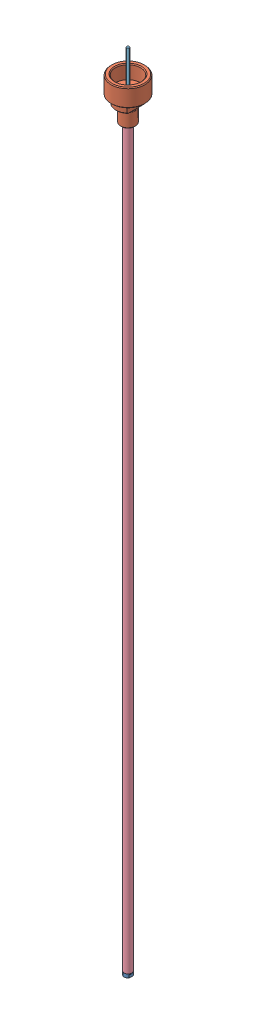
SolidWorks assembly Ensamblaje con tubo pipeta, configuration Predeterminado. Lengths in mm.
Overall size (41.58 1129.12 41.58).
5 component instances, 5 part files, 7 mates.
Components (placement in the parent):
- Boquilla de la Pipeta-1: Boquilla de la Pipeta [Predeterminado] at (-120.7009 -415.5245 82.1761) size (9.52 11 9.52)
- Buje Copa Superior-1: Buje Copa Superior [Predeterminado] at (-120.7009 493.4755 82.1761) size (41.58 52 41.58)
- Buje interior de Boquilla-1: Buje interior de Boquilla [Predeterminado] at (-120.7009 -417.399 82.1761) x (0.243661 0 -0.969861) z (0.969861 0 0.243661) size (6 4 6)
- Tubo Pipeta-1: Tubo Pipeta [Predeterminado] at (-120.7009 495.3348 82.1761) x (1 0 0.000226) z (-0.000226 0 1) size (9.52 940 9.52)
- Varilla de la pipeta-1: Varilla de la pipeta [Predeterminado] at (-120.7009 574.5117 82.1761) size (3.17 1129.12 3.17)
Mates (geometry in assembly coordinates):
- Concéntrica1: concentric aligned: cylinder of Buje Copa Superior-1 through (-120.7009 543.8505 82.1761) axis (0 1 0) radius 4.7625; cylinder of Tubo Pipeta-1 through (-120.7009 532.5941 82.1761) axis (0 1 0) radius 4.26
- Coincidente1: coincident anti-aligned: plane of Buje Copa Superior-1 through (-115.9384 523.4755 82.1761) normal (0 -1 0); plane of Tubo Pipeta-1 through (-116.4409 523.4755 82.1771) normal (0 1 0)
- Coincidente5: coincident: circle of Buje interior de Boquilla-1; cone of Varilla de la pipeta-1 through (-120.7009 -416.4449 82.1761) axis (0 -1 0)
- Coincidente6: coincident anti-aligned: plane of Boquilla de la Pipeta-1 through (-117.7009 -414.5245 82.1761) normal (0 1 0); plane of Buje interior de Boquilla-1 through (-120.3841 -414.5245 80.9153) normal (0 -1 0)
- Concéntrica4: concentric aligned: cylinder of Boquilla de la Pipeta-1 through (-120.7009 -389.2879 82.1761) axis (0 1 0) radius 3; cylinder of Varilla de la pipeta-1 through (-120.7009 585.7954 82.1761) axis (0 1 0) radius 1.5875
- Coincidente7: coincident anti-aligned: plane of Boquilla de la Pipeta-1 through (-115.9409 -410.5245 82.1761) normal (0 1 0); plane of Tubo Pipeta-1 through (-115.9409 -410.5245 82.1772) normal (0 -1 0)
- Concéntrica5: concentric aligned: cylinder of Tubo Pipeta-1 through (-120.7009 532.5941 82.1761) axis (0 1 0) radius 4.76; cylinder of Varilla de la pipeta-1 through (-120.7009 585.7954 82.1761) axis (0 1 0) radius 1.5875
